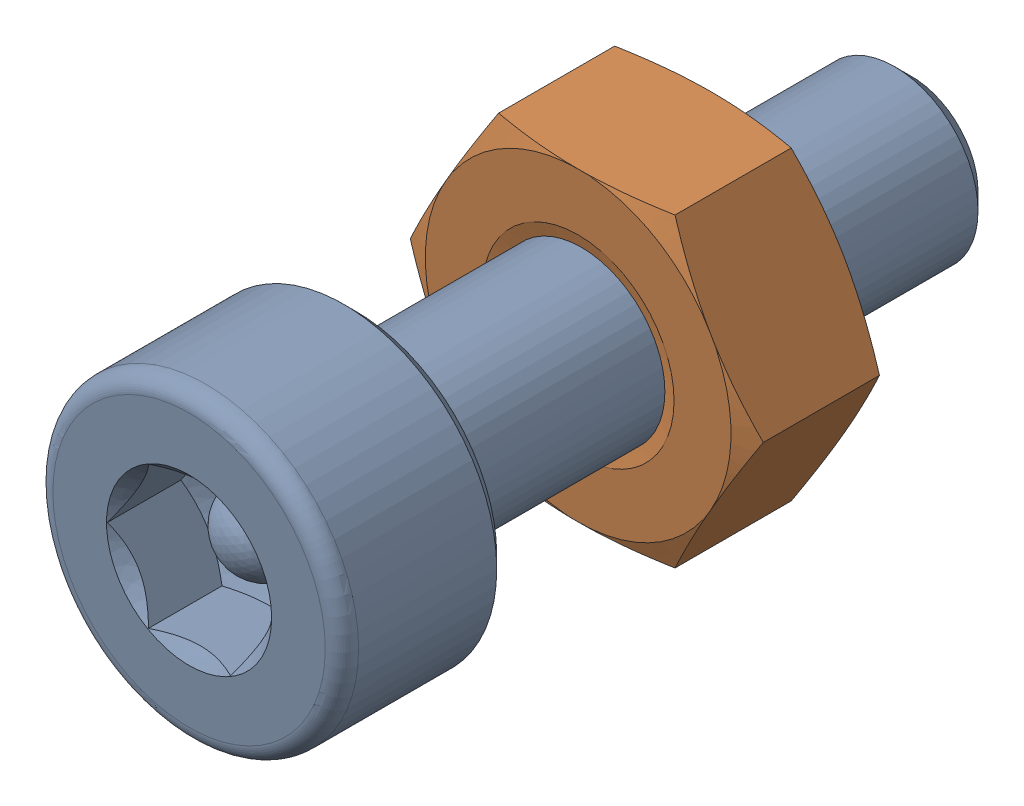
SolidWorks assembly Screw and Nut M3x010_018, configuration Varsayılan. Lengths in mm.
Overall size (6.35 5.5 13.14).
2 component instances, 2 part files, 0 mates.
Components (placement in the parent):
- M3x10-Screw017-1: M3x10-Screw017 [Varsayılan] at origin size (5.5 5.5 13.14)
- M3-Nut049-1: M3-Nut049 [Varsayılan] at (0 0 -4) x (-1 0 0) z (0 0 -1) size (6.35 5.5 2.4)
